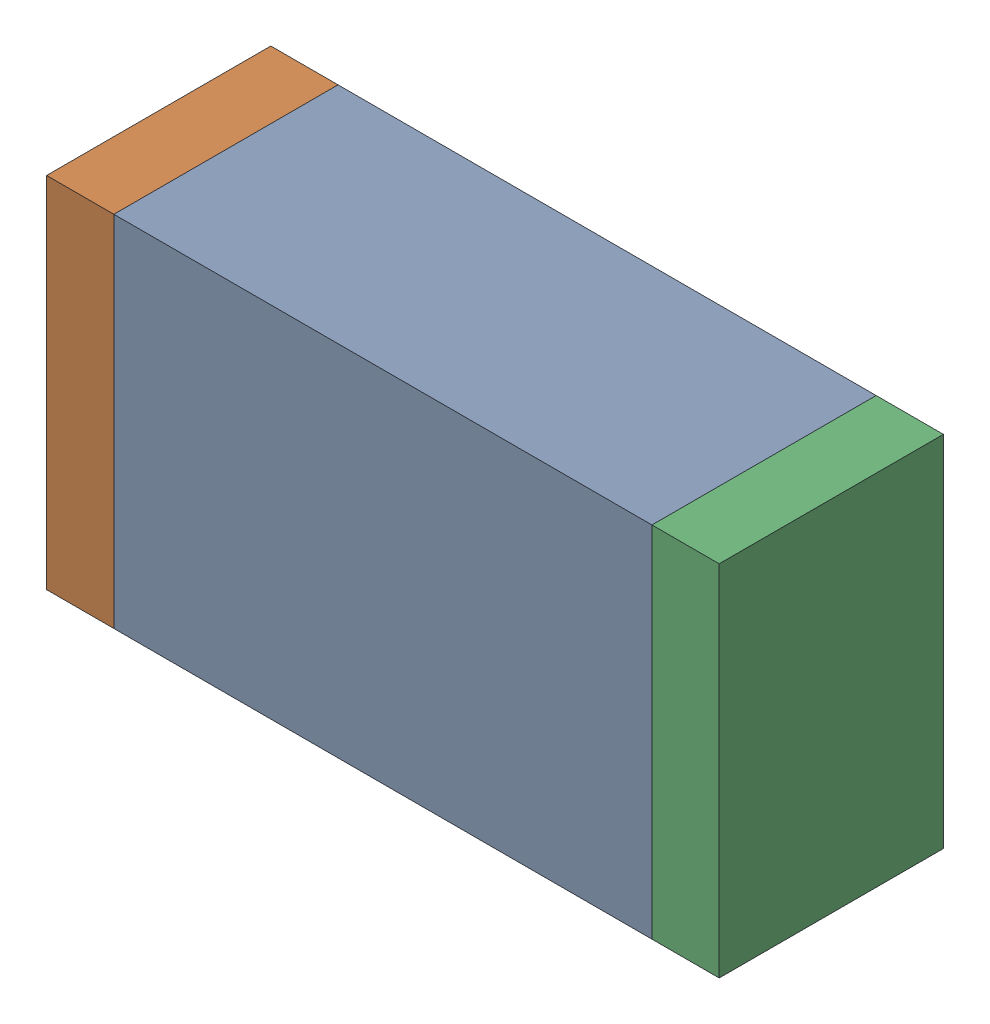
SolidWorks assembly D9, configuration Default. Lengths in mm.
Overall size (1.5 0.8 0.5).
6 component instances, 2 part files, 0 mates.
Components (placement in the parent):
- 836752368-1: 836752368 [Default] at (111.15 17.05 0) size (1.2 0.8 0.5)
  - Extruded-1: Extruded [Default] at origin size (1.2 0.8 0.5)
- 836752496-1: 836752496 [Default] at (110.475 17.05 0) size (0.15 0.8 0.5)
  - Extruded_2-1: Extruded_2 [Default] at origin size (0.15 0.8 0.5)
- 836752496-2: 836752496 [Default] at (111.825 17.05 0) size (0.15 0.8 0.5)
  - Extruded_2-1: Extruded_2 [Default] at origin size (0.15 0.8 0.5)
